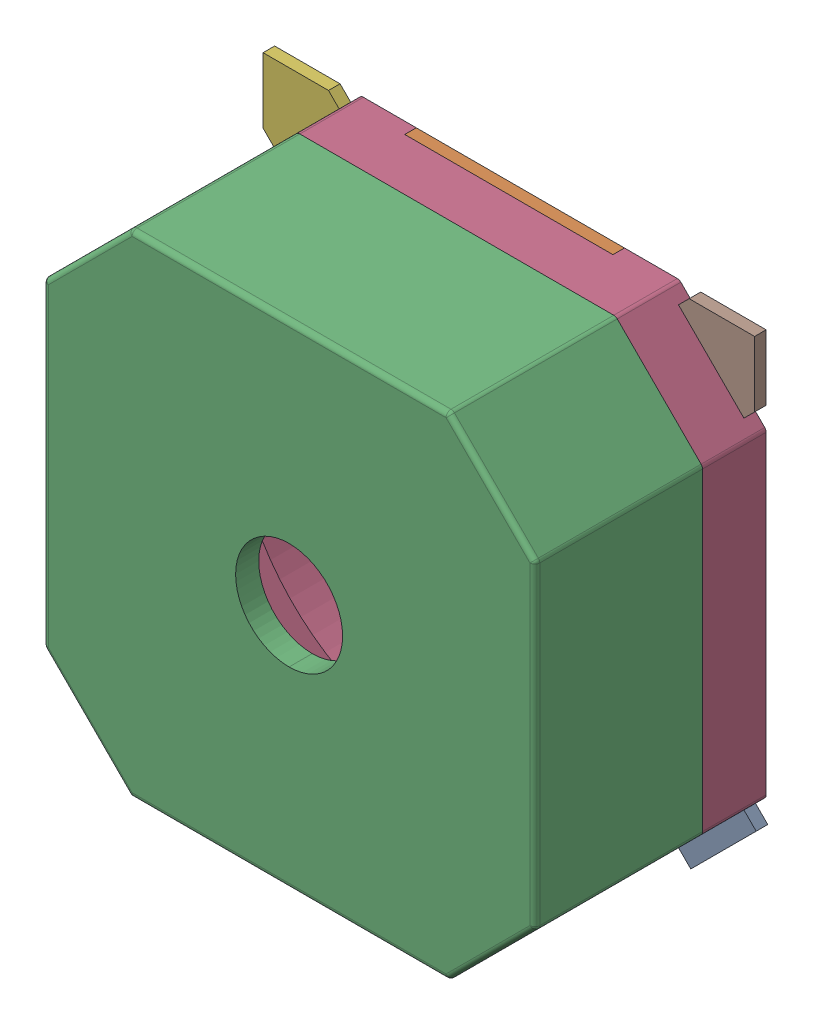
SolidWorks assembly LS1, configuration Standard. Lengths in mm.
Overall size (8.53 8.53 4).
10 component instances, 9 part files, 0 mates.
Components (placement in the parent):
- LS1-subassembly-1-1: LS1-subassembly-1 [Standard] at (11.75 13.3 0) x (1 0 0) z (0 -1 0) size (8.53 4 8.53)
  - CUI_DEVICES_CMT-8504-100-SMT-TR-1: CUI_DEVICES_CMT-8504-100-SMT-TR [Standard] at origin size (1.48 0.2 1.48)
  - CUI_DEVICES_CMT-8504-100-SMT-TR-1-1: CUI_DEVICES_CMT-8504-100-SMT-TR-1 [Standard] at origin size (3.6 0.2 1.8)
  - CUI_DEVICES_CMT-8504-100-SMT-TR-2-1: CUI_DEVICES_CMT-8504-100-SMT-TR-2 [Standard] at origin size (8.5 2.9 8.5)
  - CUI_DEVICES_CMT-8504-100-SMT-TR-3-1: CUI_DEVICES_CMT-8504-100-SMT-TR-3 [Standard] at origin size (8.5 1.5 8.5)
  - CUI_DEVICES_CMT-8504-100-SMT-TR-4-1: CUI_DEVICES_CMT-8504-100-SMT-TR-4 [Standard] at origin size (1.46 0.2 1.46)
  - CUI_DEVICES_CMT-8504-100-SMT-TR-5-1: CUI_DEVICES_CMT-8504-100-SMT-TR-5 [Standard] at origin size (1.46 0.2 1.46)
  - CUI_DEVICES_CMT-8504-100-SMT-TR-6-1: CUI_DEVICES_CMT-8504-100-SMT-TR-6 [Standard] at origin size (1 0.2 1.3)
  - CUI_DEVICES_CMT-8504-100-SMT-TR-7-1: CUI_DEVICES_CMT-8504-100-SMT-TR-7 [Standard] at origin size (1.46 0.2 1.46)
  - CUI_DEVICES_CMT-8504-100-SMT-TR-8-1: CUI_DEVICES_CMT-8504-100-SMT-TR-8 [Standard] at origin size (1 0.2 1.3)
